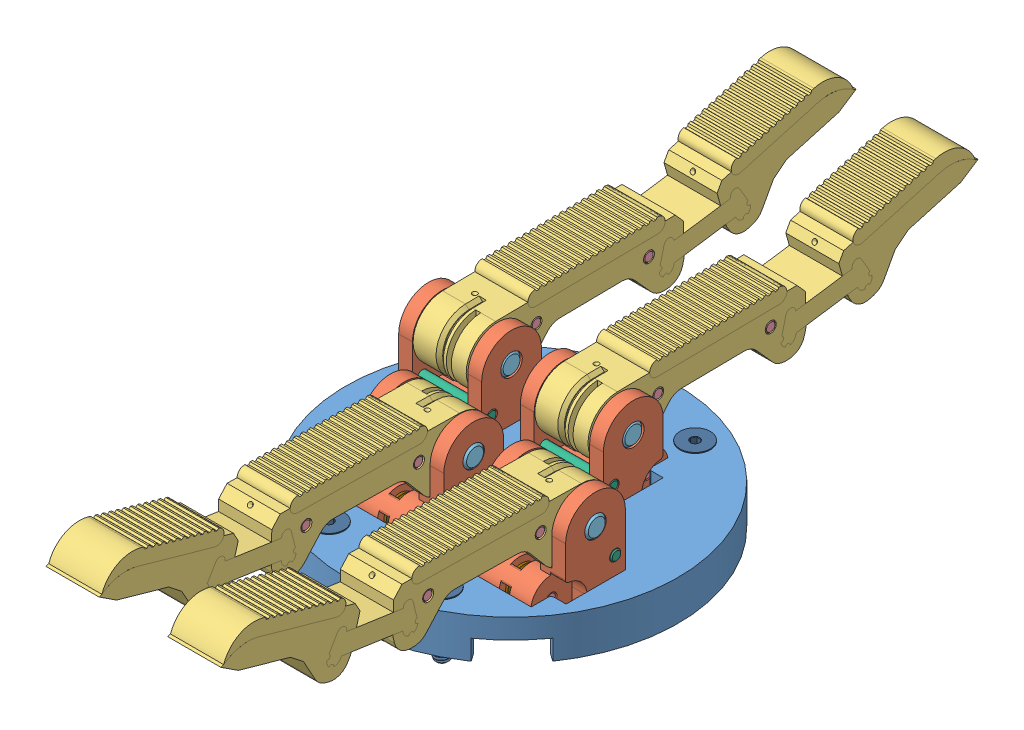
SolidWorks assembly block_top_pf_t, configuration Default. Lengths in mm.
Overall size (100 57.13 247.1).
49 component instances, 10 part files, 20 mates.
Components (placement in the parent):
- a1_p_t-1: a1_p_t [Default] at origin size (100 12 100)
- block_finger_pf_t-1: block_finger_pf_t [Default] at (9.2417 -4.5 0) size (25.4 45.69 121.76)
  - c1_t-1: c1_t [Default] at origin size (25 30.67 32)
  - t_pf-1: t_pf [Default] at (-0.15 21.67 -14.7858) x (1 0 0) z (0 -0.013363 0.999911) size (16 29.93 117.65)
  - 98381A472 D1-8 L5-8-1: 98381A472 D1-8 L5-8 [98381A472] at (-0.0875 23.995 -26.9308) size (15.88 3.17 3.17)
  - 98381A472 D1-8 L5-8-2: 98381A472 D1-8 L5-8 [98381A472] at (-0.0875 24.448 -60.8289) size (15.88 3.17 3.17)
  - 98381A542 D1-4 L1-1: 98381A542 D1-4 L1 [98381A542] at (-0.2 21.67 -14.7858) size (25.4 6.35 6.35)
  - 98381A475 D1-8 L1-1: 98381A475 D1-8 L1 [98381A475] at (-0.2 11.2575 -8.8732) size (25.4 3.17 3.17)
  - 98381A472 D1-8 L5-8-3: 98381A472 D1-8 L5-8 [98381A472] at (0.0625 4.925 -23.535) size (15.88 3.17 3.17)
  - 93365A120 4-40 insert-1: 93365A120 4-40 insert [93365A120] at (-0.15 27.5639 -100.2943) x (1 0 0) z (0 0.622567 -0.782567) size (4.37 3.82 4.37)
  - 91253A106 4-40 L1-4 countersunk-1: 91253A106 4-40 L1-4 countersunk [91253A106] at (-0.15 25.9039 -101.6148) x (1 0 0) z (0 -0.782567 -0.622567) size (6.48 6.48 6.63)
  - 3434T31 - nylon pulley-1: 3434T31 - nylon pulley [Default] at (-0.15 4.925 -23.535) x (0 -0.840446 -0.541896) z (0 -0.541896 0.840446) size (9.5 2.4 9.5)
- block_finger_pf_t-2: block_finger_pf_t [Default] at (-27.425 -4.5 0.0007) size (25.4 45.69 121.76)
  - c1_t-1: c1_t [Default] at origin size (25 30.67 32)
  - t_pf-1: t_pf [Default] at (-0.15 21.67 -14.7858) x (1 0 0) z (0 -0.013363 0.999911) size (16 29.93 117.65)
  - 98381A472 D1-8 L5-8-1: 98381A472 D1-8 L5-8 [98381A472] at (-0.0875 23.995 -26.9308) size (15.88 3.17 3.17)
  - 98381A472 D1-8 L5-8-2: 98381A472 D1-8 L5-8 [98381A472] at (-0.0875 24.448 -60.8289) size (15.88 3.17 3.17)
  - 98381A542 D1-4 L1-1: 98381A542 D1-4 L1 [98381A542] at (-0.2 21.67 -14.7858) size (25.4 6.35 6.35)
  - 98381A475 D1-8 L1-1: 98381A475 D1-8 L1 [98381A475] at (-0.2 11.2575 -8.8732) size (25.4 3.17 3.17)
  - 98381A472 D1-8 L5-8-3: 98381A472 D1-8 L5-8 [98381A472] at (0.0625 4.925 -23.535) size (15.88 3.17 3.17)
  - 93365A120 4-40 insert-1: 93365A120 4-40 insert [93365A120] at (-0.15 27.5639 -100.2943) x (1 0 0) z (0 0.622567 -0.782567) size (4.37 3.82 4.37)
  - 91253A106 4-40 L1-4 countersunk-1: 91253A106 4-40 L1-4 countersunk [91253A106] at (-0.15 25.9039 -101.6148) x (1 0 0) z (0 -0.782567 -0.622567) size (6.48 6.48 6.63)
  - 3434T31 - nylon pulley-1: 3434T31 - nylon pulley [Default] at (-0.15 4.925 -23.535) x (0 -0.840446 -0.541896) z (0 -0.541896 0.840446) size (9.5 2.4 9.5)
- block_finger_pf_t-3: block_finger_pf_t [Default] at (-9.2417 -4.5 0) x (-1 0 0) z (0 0 -1) size (25.4 45.69 121.76)
  - c1_t-1: c1_t [Default] at origin size (25 30.67 32)
  - t_pf-1: t_pf [Default] at (-0.15 21.67 -14.7858) x (1 0 0) z (0 -0.013363 0.999911) size (16 29.93 117.65)
  - 98381A472 D1-8 L5-8-1: 98381A472 D1-8 L5-8 [98381A472] at (-0.0875 23.995 -26.9308) size (15.88 3.17 3.17)
  - 98381A472 D1-8 L5-8-2: 98381A472 D1-8 L5-8 [98381A472] at (-0.0875 24.448 -60.8289) size (15.88 3.17 3.17)
  - 98381A542 D1-4 L1-1: 98381A542 D1-4 L1 [98381A542] at (-0.2 21.67 -14.7858) size (25.4 6.35 6.35)
  - 98381A475 D1-8 L1-1: 98381A475 D1-8 L1 [98381A475] at (-0.2 11.2575 -8.8732) size (25.4 3.17 3.17)
  - 98381A472 D1-8 L5-8-3: 98381A472 D1-8 L5-8 [98381A472] at (0.0625 4.925 -23.535) size (15.88 3.17 3.17)
  - 93365A120 4-40 insert-1: 93365A120 4-40 insert [93365A120] at (-0.15 27.5639 -100.2943) x (1 0 0) z (0 0.622567 -0.782567) size (4.37 3.82 4.37)
  - 91253A106 4-40 L1-4 countersunk-1: 91253A106 4-40 L1-4 countersunk [91253A106] at (-0.15 25.9039 -101.6148) x (1 0 0) z (0 -0.782567 -0.622567) size (6.48 6.48 6.63)
  - 3434T31 - nylon pulley-1: 3434T31 - nylon pulley [Default] at (-0.15 4.925 -23.535) x (0 -0.840446 -0.541896) z (0 -0.541896 0.840446) size (9.5 2.4 9.5)
- block_finger_pf_t-4: block_finger_pf_t [Default] at (27.425 -4.5 0) x (-1 0 0) z (0 0 -1) size (25.4 45.69 121.76)
  - c1_t-1: c1_t [Default] at origin size (25 30.67 32)
  - t_pf-1: t_pf [Default] at (-0.15 21.67 -14.7858) x (1 0 0) z (0 -0.013363 0.999911) size (16 29.93 117.65)
  - 98381A472 D1-8 L5-8-1: 98381A472 D1-8 L5-8 [98381A472] at (-0.0875 23.995 -26.9308) size (15.88 3.17 3.17)
  - 98381A472 D1-8 L5-8-2: 98381A472 D1-8 L5-8 [98381A472] at (-0.0875 24.448 -60.8289) size (15.88 3.17 3.17)
  - 98381A542 D1-4 L1-1: 98381A542 D1-4 L1 [98381A542] at (-0.2 21.67 -14.7858) size (25.4 6.35 6.35)
  - 98381A475 D1-8 L1-1: 98381A475 D1-8 L1 [98381A475] at (-0.2 11.2575 -8.8732) size (25.4 3.17 3.17)
  - 98381A472 D1-8 L5-8-3: 98381A472 D1-8 L5-8 [98381A472] at (0.0625 4.925 -23.535) size (15.88 3.17 3.17)
  - 93365A120 4-40 insert-1: 93365A120 4-40 insert [93365A120] at (-0.15 27.5639 -100.2943) x (1 0 0) z (0 0.622567 -0.782567) size (4.37 3.82 4.37)
  - 91253A106 4-40 L1-4 countersunk-1: 91253A106 4-40 L1-4 countersunk [91253A106] at (-0.15 25.9039 -101.6148) x (1 0 0) z (0 -0.782567 -0.622567) size (6.48 6.48 6.63)
  - 3434T31 - nylon pulley-1: 3434T31 - nylon pulley [Default] at (-0.15 4.925 -23.535) x (0 -0.840446 -0.541896) z (0 -0.541896 0.840446) size (9.5 2.4 9.5)
- 92210A197 8-32 L3-4 countersunk-1: 92210A197 8-32 L3-4 countersunk [92210A197] at (17.0093 1.7845 38.128) x (0.445326 0 -0.895368) z (0 1 0) size (9.12 9.12 19.5)
- 92210A197 8-32 L3-4 countersunk-2: 92210A197 8-32 L3-4 countersunk [92210A197] at (-17.0093 1.7845 38.128) x (1 0 0) z (0 1 0) size (9.12 9.12 19.5)
- 92210A197 8-32 L3-4 countersunk-3: 92210A197 8-32 L3-4 countersunk [92210A197] at (17.0093 1.7845 -38.128) x (0.865412 0 0.501062) z (0 1 0) size (9.12 9.12 19.5)
- 92210A197 8-32 L3-4 countersunk-4: 92210A197 8-32 L3-4 countersunk [92210A197] at (-17.0093 1.7845 -38.128) x (1 0 0) z (0 1 0) size (9.12 9.12 19.5)
Mates (geometry in assembly coordinates):
- Coincident1: coincident: plane of a1_p_t-1 through (-14.925 1.5 -5.7858) normal (-1 0 0); plane of block_finger_pf_t-2/c1_t-1 through (-14.925 17.17 -14.785) normal (1 0 0)
- Coincident2: coincident: plane of a1_p_t-1 through (-19.425 1.5 -29.7843) normal (0 0 1); plane of block_finger_pf_t-2/c1_t-1 through (-14.925 0.425 -29.7843) normal (0 0 -1)
- Coincident3: coincident: plane of a1_p_t-1 through (0 -1.5 0) normal (0 -1 0); plane of block_finger_pf_t-2/c1_t-1 through (-39.925 -1.5 -5.785) normal (0 1 0)
- Coincident4: coincident: plane of a1_p_t-1 through (21.7417 1.5 -5.7858) normal (-1 0 0); plane of block_finger_pf_t-1/c1_t-1 through (21.7417 17.17 -14.7858) normal (1 0 0)
- Coincident5: coincident: plane of a1_p_t-1 through (-3.4083 1.5 -5.7858) normal (0 0 -1); plane of block_finger_pf_t-1/c1_t-1 through (-3.2583 17.17 -5.7858) normal (0 0 1)
- Coincident6: coincident: plane of a1_p_t-1 through (0 -1.5 0) normal (0 -1 0); plane of block_finger_pf_t-1/c1_t-1 through (-3.2583 -1.5 -5.7858) normal (0 1 0)
- Coincident7: coincident: plane of a1_p_t-1 through (14.925 1.5 5.7858) normal (1 0 0); plane of block_finger_pf_t-4/c1_t-1 through (14.925 17.17 14.7858) normal (-1 0 0)
- Coincident8: coincident: plane of a1_p_t-1 through (40.075 1.5 5.7858) normal (0 0 1); plane of block_finger_pf_t-4/c1_t-1 through (39.925 17.17 5.7858) normal (0 0 -1)
- Coincident9: coincident: plane of a1_p_t-1 through (0 -1.5 0) normal (0 -1 0); plane of block_finger_pf_t-4/c1_t-1 through (39.925 -1.5 33.785) normal (0 1 0)
- Coincident10: coincident: plane of a1_p_t-1 through (-21.7417 1.5 23.7858) normal (1 0 0); plane of block_finger_pf_t-3/c1_t-1 through (-21.7417 17.17 14.7858) normal (-1 0 0)
- Coincident11: coincident: plane of a1_p_t-1 through (-21.7417 1.5 5.7858) normal (0 0 1); plane of block_finger_pf_t-3/c1_t-1 through (3.2583 17.17 5.7858) normal (0 0 -1)
- Coincident12: coincident: plane of a1_p_t-1 through (0 -1.5 0) normal (0 -1 0); plane of block_finger_pf_t-3/c1_t-1 through (3.2583 -1.5 5.7858) normal (0 1 0)
- Concentric1: concentric: cylinder of a1_p_t-1 through (17.0093 1.5 38.128) axis (0 1 0) radius 2.4574; circle of 92210A197 8-32 L3-4 countersunk-1
- Coincident13: coincident: cone of a1_p_t-1 through (17.0093 1.5 38.128) axis (0 -1 0); cone of 92210A197 8-32 L3-4 countersunk-1 through (17.0093 -1.0603 38.128) axis (0 -1 0)
- Concentric3: concentric: cylinder of a1_p_t-1 through (17.0093 1.5 -38.128) axis (0 1 0) radius 2.4574; circle of 92210A197 8-32 L3-4 countersunk-3
- Coincident14: coincident: cone of a1_p_t-1 through (17.0093 1.5 -38.128) axis (0 -1 0); cone of 92210A197 8-32 L3-4 countersunk-3 through (17.0093 -1.0603 -38.128) axis (0 -1 0)
- Concentric5: concentric: cylinder of a1_p_t-1 through (-17.0093 1.5 -38.128) axis (0 1 0) radius 2.4574; circle of 92210A197 8-32 L3-4 countersunk-4
- Coincident15: coincident: cone of a1_p_t-1 through (-17.0093 1.5 -38.128) axis (0 -1 0); cone of 92210A197 8-32 L3-4 countersunk-4 through (-17.0093 -1.0603 -38.128) axis (0 -1 0)
- Concentric7: concentric: cylinder of a1_p_t-1 through (-17.0093 1.5 38.128) axis (0 1 0) radius 2.4574; circle of 92210A197 8-32 L3-4 countersunk-2
- Coincident16: coincident: cone of a1_p_t-1 through (-17.0093 1.5 38.128) axis (0 -1 0); cone of 92210A197 8-32 L3-4 countersunk-2 through (-17.0093 -1.0603 38.128) axis (0 -1 0)
